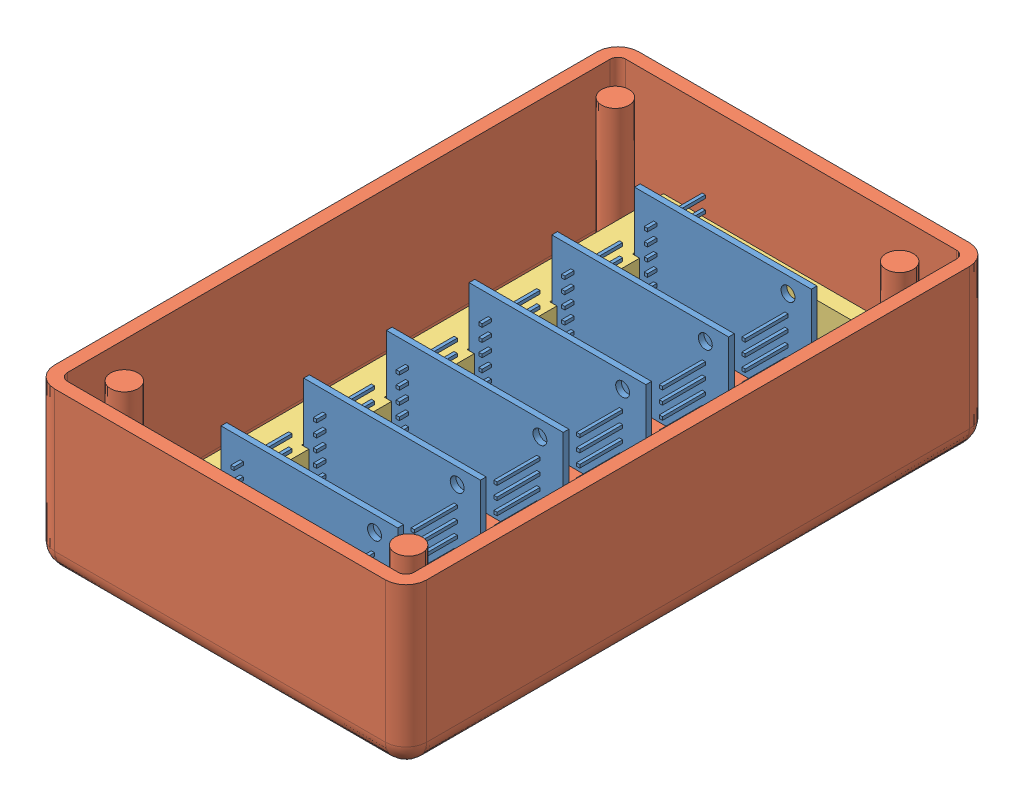
SolidWorks assembly Boitier, configuration Défaut. Lengths in mm.
Overall size (72 31.2 113).
8 component instances, 3 part files, 7 mates.
Components (placement in the parent):
- Capteur_HX711^Boitier-1: Capteur_HX711^Boitier [Défaut] at (17 13.2 -42) x (0 1 0) z (0 0 1) size (21 34.2 17.7) (virtual)
- Capteur_HX711^Boitier-7: Capteur_HX711^Boitier [Défaut] at (17 13.2 -26) x (0 1 0) z (0 0 1) size (21 34.2 17.7) (virtual)
- Capteur_HX711^Boitier-8: Capteur_HX711^Boitier [Défaut] at (17 13.2 -10) x (0 1 0) z (0 0 1) size (21 34.2 17.7) (virtual)
- Capteur_HX711^Boitier-9: Capteur_HX711^Boitier [Défaut] at (17 13.2 6) x (0 1 0) z (0 0 1) size (21 34.2 17.7) (virtual)
- Capteur_HX711^Boitier-10: Capteur_HX711^Boitier [Défaut] at (17 13.2 22) x (0 1 0) z (0 0 1) size (21 34.2 17.7) (virtual)
- Capteur_HX711^Boitier-11: Capteur_HX711^Boitier [Défaut] at (17 13.2 38) x (0 1 0) z (0 0 1) size (21 34.2 17.7) (virtual)
- Boitier^Boitier-1: Boitier^Boitier [Défaut] x (0 0 -1) z (1 0 0) size (113 31.2 72) (virtual)
- Rack^Boitier-1: Rack^Boitier [Défaut] at origin size (49 10 107.6) (virtual)
Mates (geometry in assembly coordinates):
- Coïncidente11: coincident aligned: plane of Boitier^Boitier-1; plane of assembly through (0 0 0) normal (0 1 0)
- Coïncidente12: coincident anti-aligned: plane of Boitier^Boitier-1 through (0 0 0) normal (0 0 -1); plane of assembly through (0 0 0) normal (0 0 1)
- Coïncidente13: coincident aligned: plane of Boitier^Boitier-1 through (0 0 0) normal (1 0 0); plane of assembly through (0 0 0) normal (1 0 0)
- Parallèle1: parallel anti-aligned: plane of Capteur_HX711^Boitier-1 through (17 13.2 -42) normal (0 0 -1); plane of assembly through (0 0 0) normal (0 0 1)
- Distance1: distance = 0.2 mm anti-aligned: plane of Capteur_HX711^Boitier-1 through (-17.2 2.7 -40.9) normal (0 -1 0); plane of Boitier^Boitier-1 through (0 2.5 0) normal (0 1 0)
- Distance2: distance = 12 mm anti-aligned: plane of Capteur_HX711^Boitier-1 through (17 13.2 -42) normal (0 0 -1); plane of Boitier^Boitier-1 through (-36 31.2 -54) normal (0 0 1)
- Distance3: distance = 16.5 mm anti-aligned: plane of Boitier^Boitier-1 through (33.5 31.2 56.5) normal (-1 0 0); plane of Capteur_HX711^Boitier-1 through (17 2.7 -40.9) normal (1 0 0)
